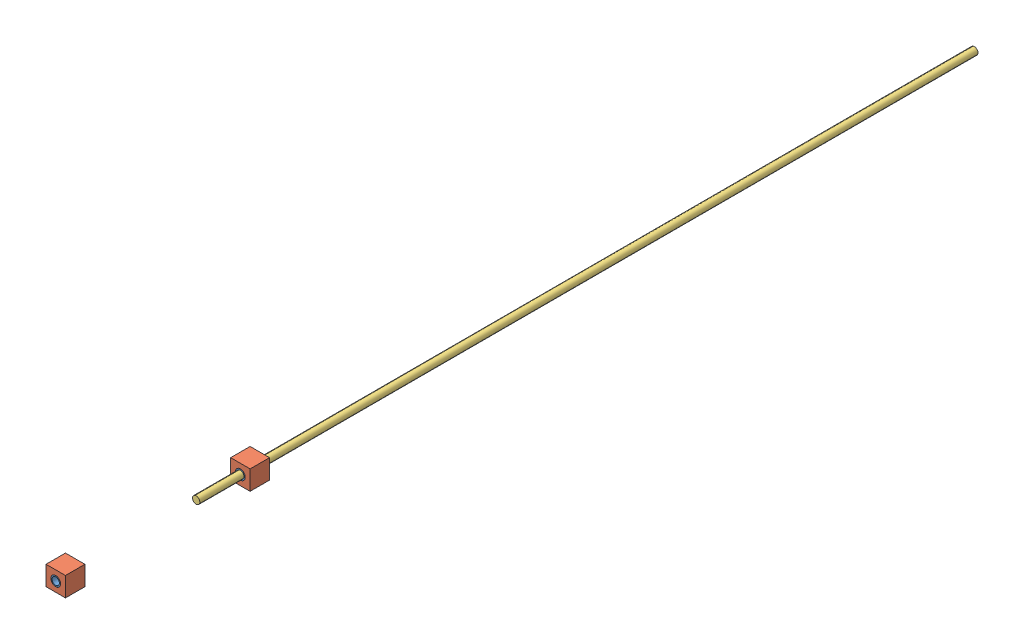
SolidWorks assembly Rods and blocks, configuration Default. Lengths in mm.
Overall size (25.4 25.4 2133.6).
7 component instances, 3 part files, 3 mates.
Components (placement in the parent):
- Wood block w fitting-1: Wood block w fitting [Default] at (-8.5081 14.9168 27.8604) size (25.4 25.4 25.4)
  - Bronze fitting-1: Bronze fitting [Default] at (16.3355 20.1904 11.168) size (12.7 12.7 25.4)
  - Wood block-1: Wood block [Default] at (3.6355 7.4904 11.168) size (25.4 25.4 25.4)
- Wood block w fitting-2: Wood block w fitting [Default] at (-12.363 51.4427 268.9152) x (0 -1 0) z (0 0 1) size (25.4 25.4 25.4)
  - Bronze fitting-1: Bronze fitting [Default] at (16.3355 20.1904 11.168) size (12.7 12.7 25.4)
  - Wood block-1: Wood block [Default] at (3.6355 7.4904 11.168) size (25.4 25.4 25.4)
- Steel Rod-1: Steel Rod [Default] at (7.8274 35.1072 -893.8752) x (-0.308956 0.951076 0) z (0 0 1) size (9.53 9.53 1016)
Mates (geometry in assembly coordinates):
- Concentric2: concentric aligned: circle of Wood block w fitting-1/Bronze fitting-1; circle of Steel Rod-1
- Concentric3: concentric aligned: circle of Wood block w fitting-2/Bronze fitting-1; circle of Steel Rod-1
- Parallel1: parallel aligned: plane of Wood block w fitting-1/Wood block-1 through (-4.8726 22.4072 64.4284) normal (0 -1 0); plane of Wood block w fitting-2/Wood block-1 through (-4.8726 22.4072 305.4832) normal (0 -1 0)
